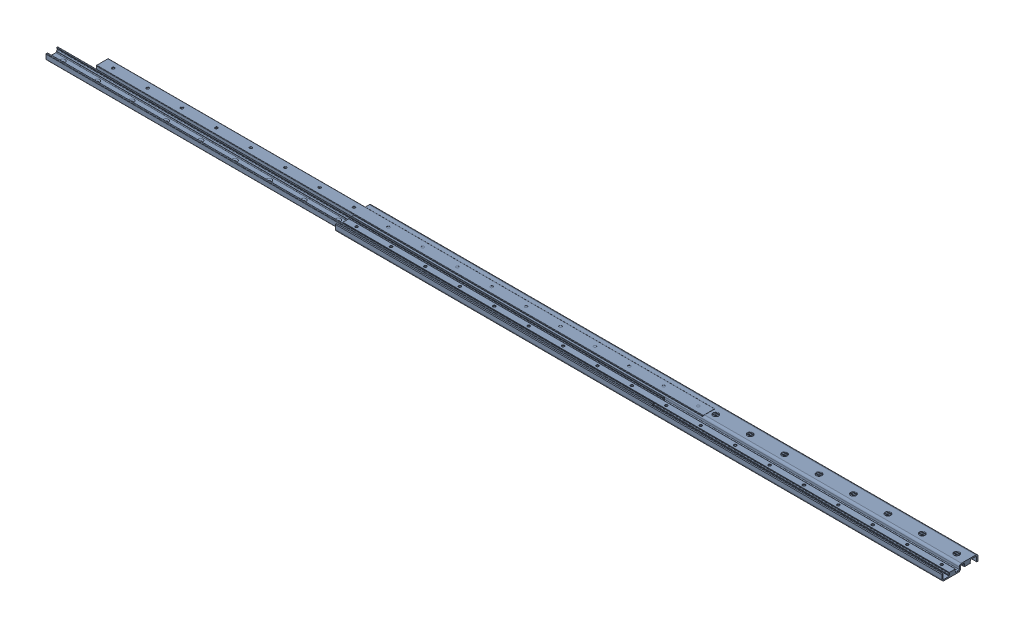
SolidWorks assembly MirrorDSD28-1410-2, configuration Default. Lengths in mm.
Overall size (1410 17 84).
3 component instances, 3 part files, 8 mates.
Components (placement in the parent):
- ROLLCO-DS28-BRAKET2X-ASN28-Slider-1: ROLLCO-DS28-BRAKET2X-ASN28-Slider [Default] at (-683 0.5 -3.836) size (1410 15 84)
- ROLLCO-ASN28-Rail-1: ROLLCO-ASN28-Rail [Default] at (-1280.1362 0 -35) size (1410 12.25 28)
- ROLLCO-ASN28-Rail_2-1: ROLLCO-ASN28-Rail_2 [Default] at (-1366 1 31.2009) size (1410 12.25 28)
Mates (geometry in assembly coordinates):
- Parallel1: parallel aligned: plane of ROLLCO-DS28-BRAKET2X-ASN28-Slider-1 through (-683 0.5 -3.836) normal (-1 0 0); plane of ROLLCO-ASN28-Rail-1 through (-1280.1362 0 -35) normal (-1 0 0)
- Parallel2: parallel aligned: plane of ROLLCO-DS28-BRAKET2X-ASN28-Slider-1 through (-683 0.5 38.164) normal (0 0 1); plane of ROLLCO-ASN28-Rail-1 through (-1280.1362 0 -3.5) normal (0 0 1)
- Distance1: distance = 2 mm anti-aligned: plane of ROLLCO-DS28-BRAKET2X-ASN28-Slider-1 through (-683 3.5 -3.836) normal (0 1 0); plane of ROLLCO-ASN28-Rail-1 through (-1280.1362 5.5 -35) normal (0 -1 0)
- Parallel3: parallel aligned: plane of ROLLCO-DS28-BRAKET2X-ASN28-Slider-1 through (727 0.5 -3.836) normal (1 0 0); plane of ROLLCO-ASN28-Rail_2-1 through (44 1 31.2009) normal (1 0 0)
- Parallel4: parallel anti-aligned: plane of ROLLCO-DS28-BRAKET2X-ASN28-Slider-1 through (-683 0.5 -45.836) normal (0 0 -1); plane of ROLLCO-ASN28-Rail_2-1 through (-1366 1 27.7009) normal (0 0 1)
- Distance2: distance = 2 mm anti-aligned: plane of ROLLCO-ASN28-Rail_2-1 through (-1366 -4.5 31.2009) normal (0 1 0); plane of ROLLCO-DS28-BRAKET2X-ASN28-Slider-1 through (-683 -2.5 -3.836) normal (0 -1 0)
- LimitDistance1: limit distance = 683 mm aligned: plane of ROLLCO-ASN28-Rail_2-1 through (-1366 1 31.2009) normal (-1 0 0); plane of ROLLCO-DS28-BRAKET2X-ASN28-Slider-1 through (-683 0.5 -3.836) normal (-1 0 0)
- LimitDistance2: limit distance = 597.1362 mm aligned: plane of ROLLCO-DS28-BRAKET2X-ASN28-Slider-1 through (-683 0.5 -3.836) normal (-1 0 0); plane of ROLLCO-ASN28-Rail-1 through (-1280.1362 0 -35) normal (-1 0 0)
